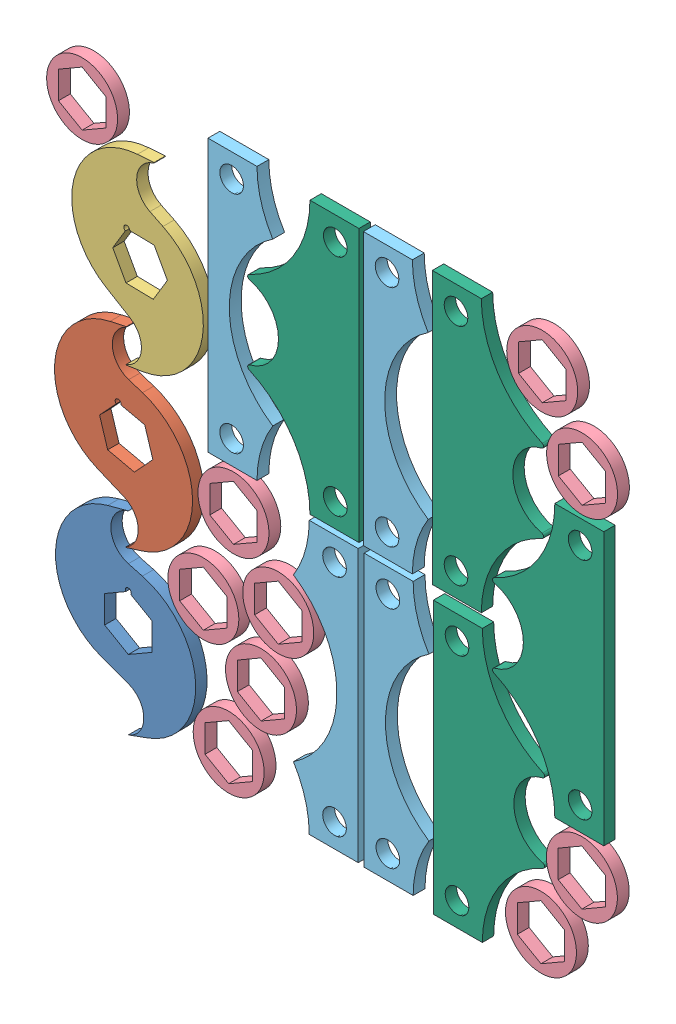
SolidWorks assembly Flatt_Pattern_1, configuration Default. Lengths in mm.
Overall size (306.52 305.59 6.35).
21 component instances, 6 part files, 26 mates.
Components (placement in the parent):
- 2Tooth_Cutter_V1-1: 2Tooth_Cutter_V1 [Default] at (43.1713 55.1568 -3.048) size (75.28 104.14 6.1)
- 2Tooth_Cutter_V1_2-1: 2Tooth_Cutter_V1_2 [Default] at (42.0456 140.8872 -3.048) x (0.998865 -0.047631 0) z (0 0 1) size (75.28 102.63 6.1)
- 2Tooth_Cutter_V1_3-1: 2Tooth_Cutter_V1_3 [Default] at (49.4846 225.1682 -3.048) x (0.981525 -0.191336 0) z (0 0 1) size (75.28 102.63 6.1)
- Hex_Spacer-1: Hex_Spacer [Default] at (97.0535 22.0002 -3.175) size (38.1 38.1 6.35)
- Hex_Spacer-2: Hex_Spacer [Default] at (114.4073 59.8201 -3.175) size (38.1 38.1 6.35)
- Hex_Spacer-3: Hex_Spacer [Default] at (83.4369 86.5445 -3.175) size (38.1 38.1 6.35)
- Hex_Spacer-4: Hex_Spacer [Default] at (123.6696 100.1716 -3.175) size (38.1 38.1 6.35)
- Spacer_1-1: Spacer_1 [Default] at (147.5419 78.4145 -3.175) size (34.77 146.05 6.35)
- Spacer_2-1: Spacer_2 [Default] at (147.9275 227.4455 -3.048) size (59.73 146.05 6.1)
- Spacer_1-2: Spacer_1 [Default] at (105.0077 228.9373 -3.175) x (-1 0 0) z (0 0 1) size (34.77 146.05 6.35)
- Hex_Spacer-5: Hex_Spacer [Default] at (99.6153 134.5566 -3.175) size (38.1 38.1 6.35)
- Spacer_2-3: Spacer_2 [Default] at (225.9869 74.6113 -3.048) x (-1 0 0) z (0 0 1) size (59.73 146.05 6.1)
- Spacer_2-4: Spacer_2 [Default] at (279.3984 152.1547 -3.048) size (59.73 146.05 6.1)
- Spacer_2-5: Spacer_2 [Default] at (225.4553 227.6504 -3.048) x (-1 0 0) z (0 0 1) size (59.73 146.05 6.1)
- Spacer_1-3: Spacer_1 [Default] at (188.8463 77.8971 -3.175) x (-1 0 0) z (0 0 1) size (34.77 146.05 6.35)
- Spacer_1-4: Spacer_1 [Default] at (188.4342 227.2147 -3.175) x (-1 0 0) z (0 0 1) size (34.77 146.05 6.35)
- Hex_Spacer-6: Hex_Spacer [Default] at (286.6743 58.5119 -3.175) size (38.1 38.1 6.35)
- Hex_Spacer-7: Hex_Spacer [Default] at (286.7813 246.3115 -3.175) size (38.1 38.1 6.35)
- Hex_Spacer-8: Hex_Spacer [Default] at (264.7162 22.1289 -3.175) size (38.1 38.1 6.35)
- Hex_Spacer-9: Hex_Spacer [Default] at (265.3737 283.2796 -3.175) size (38.1 38.1 6.35)
- Hex_Spacer-10: Hex_Spacer [Default] at (18.3621 286.5351 -3.175) size (38.1 38.1 6.35)
Mates (geometry in assembly coordinates):
- Coincident2: coincident: plane of 2Tooth_Cutter_V1-1 through (43.1713 55.1568 0) normal (0 0 1); plane of 2Tooth_Cutter_V1_2-1 through (42.0456 140.8872 0) normal (0 0 1)
- Coincident3: coincident: plane of 2Tooth_Cutter_V1_2-1 through (42.0456 140.8872 0) normal (0 0 1); plane of 2Tooth_Cutter_V1_3-1 through (49.4846 225.1682 0) normal (0 0 1)
- Coincident4: coincident: plane of 2Tooth_Cutter_V1_2-1 through (42.0456 140.8872 0) normal (0 0 1); plane of assembly through (0 0 0) normal (0 0 1)
- Coincident5: coincident: plane of 2Tooth_Cutter_V1-1 through (43.1713 55.1568 0) normal (0 0 1); plane of Hex_Spacer-1 through (97.0535 22.0002 0) normal (0 0 1)
- Coincident6: coincident: plane of Hex_Spacer-1 through (97.0535 22.0002 0) normal (0 0 1); plane of Hex_Spacer-2 through (114.4073 59.8201 0) normal (0 0 1)
- Coincident7: coincident: plane of 2Tooth_Cutter_V1-1 through (43.1713 55.1568 0) normal (0 0 1); plane of Hex_Spacer-3 through (83.4369 86.5445 0) normal (0 0 1)
- Coincident8: coincident: plane of 2Tooth_Cutter_V1-1 through (43.1713 55.1568 0) normal (0 0 1); plane of Hex_Spacer-4 through (123.6696 100.1716 0) normal (0 0 1)
- Coincident9: coincident: plane of 2Tooth_Cutter_V1-1 through (43.1713 55.1568 0) normal (0 0 1); plane of Spacer_1-1 through (147.5419 78.4145 0) normal (0 0 1)
- Coincident10: coincident: plane of Spacer_1-1 through (147.5419 78.4145 0) normal (0 0 1); plane of Spacer_2-1 through (147.9275 227.4455 0) normal (0 0 1)
- Parallel1: parallel: line of Spacer_1-2 through (85.9577 301.9623 0) axis (0 -1 0); line of assembly
- Coincident14: coincident: plane of Spacer_2-1 through (147.9275 227.4455 0) normal (0 0 1); plane of Spacer_1-2 through (105.0077 228.9373 0) normal (0 0 1)
- Coincident15: coincident: plane of Spacer_2-1 through (147.9275 227.4455 0) normal (0 0 1); plane of Spacer_1-2 through (105.0077 228.9373 0) normal (0 0 1)
- Coincident16: coincident: plane of Spacer_1-1 through (147.5419 78.4145 0) normal (0 0 1); plane of Hex_Spacer-5 through (99.6153 134.5566 0) normal (0 0 1)
- Coincident17: coincident: plane of Spacer_1-1 through (147.5419 78.4145 0) normal (0 0 1); plane of Spacer_2-1 through (147.9275 227.4455 0) normal (0 0 1)
- Coincident18: coincident: plane of Spacer_1-1 through (147.5419 78.4145 0) normal (0 0 1); plane of Spacer_2-4 through (279.3984 152.1547 0) normal (0 0 1)
- Coincident19: coincident: plane of Spacer_2-3 through (225.9869 74.6113 0) normal (0 0 1); plane of Spacer_2-4 through (279.3984 152.1547 0) normal (0 0 1)
- Coincident20: coincident: plane of Spacer_1-1 through (147.5419 78.4145 0) normal (0 0 1); plane of Spacer_1-3 through (188.8463 77.8971 0) normal (0 0 1)
- Coincident21: coincident: plane of Spacer_1-1 through (147.5419 78.4145 0) normal (0 0 1); plane of Spacer_2-5 through (225.4553 227.6504 0) normal (0 0 1)
- Parallel2: parallel: line of Spacer_2-3 through (206.9369 147.6363 0) axis (0 -1 0); line of assembly
- Parallel3: parallel: line of Spacer_2-5 through (206.4053 300.6754 0) axis (0 -1 0); line of assembly
- Coincident28: coincident: plane of Spacer_2-1 through (147.9275 227.4455 0) normal (0 0 1); plane of Spacer_1-4 through (188.4342 227.2147 0) normal (0 0 1)
- Coincident29: coincident: plane of Spacer_2-3 through (225.9869 74.6113 0) normal (0 0 1); plane of Hex_Spacer-6 through (286.6743 58.5119 0) normal (0 0 1)
- Coincident30: coincident: plane of Spacer_2-3 through (225.9869 74.6113 0) normal (0 0 1); plane of Hex_Spacer-8 through (264.7162 22.1289 0) normal (0 0 1)
- Coincident31: coincident: plane of Spacer_2-5 through (225.4553 227.6504 0) normal (0 0 1); plane of Hex_Spacer-7 through (286.7813 246.3115 0) normal (0 0 1)
- Coincident32: coincident: plane of Hex_Spacer-7 through (286.7813 246.3115 0) normal (0 0 1); plane of Hex_Spacer-9 through (265.3737 283.2796 0) normal (0 0 1)
- Coincident33: coincident: plane of 2Tooth_Cutter_V1_3-1 through (49.4846 225.1682 0) normal (0 0 1); plane of Hex_Spacer-10 through (18.3621 286.5351 0) normal (0 0 1)
